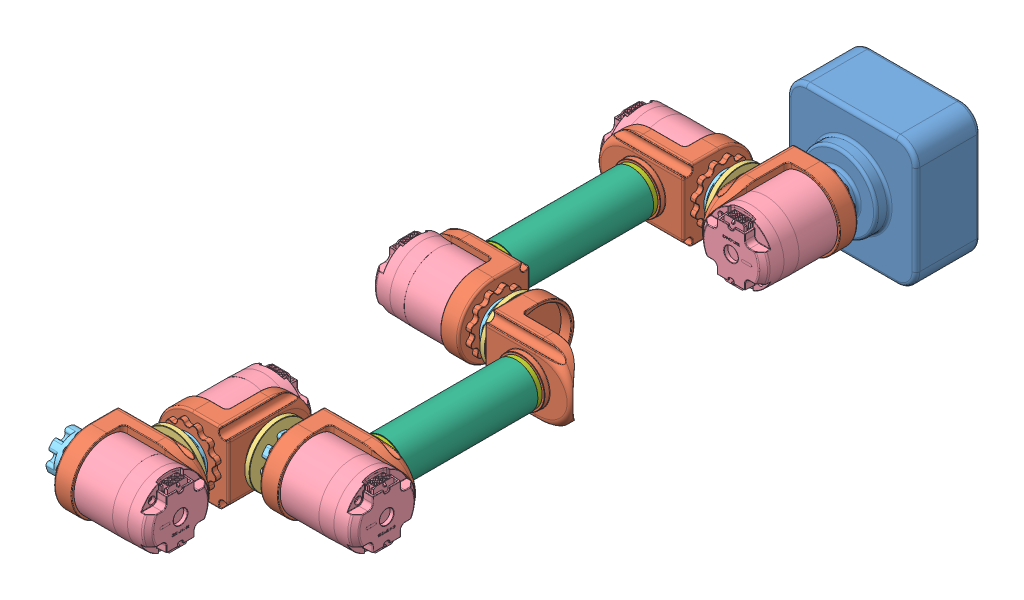
SolidWorks assembly Gluon_6L3_v1_8_1, configuration Default. Lengths in mm.
Overall size (176.02 100 561.85).
34 component instances, 7 part files, 17 mates.
Components (placement in the parent):
- L0-1: L0 [Default] at origin size (100 100 68.87)
- L1^Gluon_6L3_v1_8_1-1: L1^Gluon_6L3_v1_8_1 [Default] at (0.8406 -104.0226 74.9697) size (63.62 67.02 74.77) (virtual)
  - µç»ú¹Ì¶¨¼ÜNE30-1: µç»ú¹Ì¶¨¼ÜNE30 [Default] at (-14.7057 104.0226 11.9) x (0 -1 0) z (0 0 -1) size (55.79 59.62 71.05)
  - Á¬½ÓÅÌNE30-1: Á¬½ÓÅÌNE30 [Default] at (-36.5707 104.0226 30.0576) x (0 0.710457 -0.703741) z (1 0 0) size (47.39 47.39 4)
  - QDD_Lite_NE30-36_v1_8.step-1: QDD_Lite_NE30-36_v1_8.step [Default] at (-0.8163 104.0453 80.659) x (-0.000016 -1 0) z (1 -0.000016 0) size (52.05 68.77 52.02)
- L2^Gluon_6L3_v1_8_1-1: L2^Gluon_6L3_v1_8_1 [Default] at (0.8406 -104.0226 74.9697) size (82.97 55.79 230.2) (virtual)
  - L6-1: L6 [Default] at (-46.7717 104.0226 30.0576) x (0 0.876428 0.481534) z (1 0 0) size (31.45 31.45 14.2)
  - µç»ú¹Ì¶¨¼ÜNE30-1: µç»ú¹Ì¶¨¼ÜNE30 [Default] at (-62.7717 104.0226 43.9226) x (0 1 0) z (1 0 0) size (55.79 59.62 71.05)
  - 30Ì¼¹Ü-1: 30Ì¼¹Ü [Default] at (-80.9293 104.0226 65.7877) x (0.984241 -0.176833 0) z (0 0 1) size (34.33 34.33 102.96)
  - 30Ì¼¹ÜÁ¬½Ó¼þ-1: 30Ì¼¹ÜÁ¬½Ó¼þ [Default] at (-80.9293 104.0226 61.7877) x (0.957931 0.287 0) z (0 0 1) size (33.61 33.61 4)
  - 30Ì¼¹ÜÁ¬½Ó¼þ-2: 30Ì¼¹ÜÁ¬½Ó¼þ [Default] at (-80.9293 104.0226 168.7477) size (33.61 33.61 4)
  - µç»ú¹Ì¶¨¼ÜNE30-2: µç»ú¹Ì¶¨¼ÜNE30 [Default] at (-62.7717 104.0226 190.6128) x (0 -1 0) z (1 0 0) size (55.79 59.62 71.05)
  - L6-2: L6 [Default] at (-46.7717 104.0226 204.4778) x (0 -0.572592 -0.819841) z (1 0 0) size (31.45 31.45 14.2)
  - QDD_Lite_NE30-36_v1_8.step-1: QDD_Lite_NE30-36_v1_8.step [Default] at (-131.5308 104.0453 204.5021) x (0 -1 -0.000016) z (0 -0.000016 1) size (52.05 68.77 52.02)
  - QDD_Lite_NE30-36_v1_8.step-2: QDD_Lite_NE30-36_v1_8.step [Default] at (-131.5308 103.9999 30.0332) x (0 1 0.000016) z (0 0.000016 -1) size (52.05 68.77 52.02)
- L3^Gluon_6L3_v1_8_1-1: L3^Gluon_6L3_v1_8_1 [Default] at (0.8406 -104.0226 74.9697) size (82.97 63.95 234.28) (virtual)
  - L6-1: L6 [Default] at (-30.5707 104.0226 378.8981) x (0 -0.388976 0.921248) z (-1 0 0) size (31.45 31.45 14.2)
  - 30Ì¼¹Ü-1: 30Ì¼¹Ü [Default] at (3.5869 104.0226 240.2079) x (0.999795 0.020268 0) z (0 0 1) size (34.33 34.33 102.96)
  - 30Ì¼¹ÜÁ¬½Ó¼þ-1: 30Ì¼¹ÜÁ¬½Ó¼þ [Default] at (3.5869 104.0226 236.2079) x (0.999973 0.007346 0) z (0 0 1) size (33.61 33.61 4)
  - Á¬½ÓÅÌNE30-1: Á¬½ÓÅÌNE30 [Default] at (-36.5707 104.0226 204.4778) x (0 -0.463223 0.886242) z (1 0 0) size (47.39 47.39 4)
  - µç»ú¹Ì¶¨¼ÜNE30-1: µç»ú¹Ì¶¨¼ÜNE30 [Default] at (-14.5707 104.0226 218.3429) x (0 -1 0) z (-1 0 0) size (55.79 59.62 71.05)
  - µç»ú¹Ì¶¨¼ÜNE30-2: µç»ú¹Ì¶¨¼ÜNE30 [Default] at (-14.5707 104.0226 365.033) x (0 1 0) z (-1 0 0) size (55.79 59.62 71.05)
  - 30Ì¼¹ÜÁ¬½Ó¼þ-2: 30Ì¼¹ÜÁ¬½Ó¼þ [Default] at (3.5869 104.0226 343.1679) size (33.61 33.61 4)
  - QDD_Lite_NE30-36_v1_8.step-1: QDD_Lite_NE30-36_v1_8.step [Default] at (54.1883 103.9999 378.9224) x (0 1 -0.000016) z (0 0.000016 1) size (52.05 68.77 52.02)
- L4^Gluon_6L3_v1_8_1-1: L4^Gluon_6L3_v1_8_1 [Default] at (0.8406 -104.0226 74.9697) size (63.62 55.79 82.97) (virtual)
  - µç»ú¹Ì¶¨¼ÜNE30-1: µç»ú¹Ì¶¨¼ÜNE30 [Default] at (-62.6368 104.0226 397.0557) x (0 -1 0) z (0 0 1) size (55.79 59.62 71.05)
  - L6-1: L6 [Default] at (-76.5019 104.0226 413.0557) x (0.802011 0.597309 0) z (0 0 1) size (31.45 31.45 14.2)
  - Á¬½ÓÅÌNE30-1: Á¬½ÓÅÌNE30 [Default] at (-44.7717 104.0226 378.8981) x (0 0 -1) z (1 0 0) size (47.39 47.39 4)
  - QDD_Lite_NE30-36_v1_8.step-1: QDD_Lite_NE30-36_v1_8.step [Default] at (-76.5262 104.0453 328.2967) x (0.000016 -1 0) z (-1 -0.000016 0) size (52.05 68.77 52.02)
- L5^Gluon_6L3_v1_8_1-1: L5^Gluon_6L3_v1_8_1 [Default] at (0.8406 -104.0226 74.9697) size (88.97 55.79 63.62) (virtual)
  - µç»ú¹Ì¶¨¼ÜNE30-1: µç»ú¹Ì¶¨¼ÜNE30 [Default] at (-94.6595 104.0226 445.1217) x (0 1 0) z (-1 0 0) size (55.79 59.62 71.05)
  - Á¬½ÓÅÌNE30-1: Á¬½ÓÅÌNE30 [Default] at (-76.5019 104.0226 423.2567) x (0.999311 0.037115 0) z (0 0 1) size (47.39 47.39 4)
  - QDD_Lite_NE30-36_v1_8.step-1: QDD_Lite_NE30-36_v1_8.step [Default] at (-25.9005 103.9999 459.0111) x (0 1 -0.000016) z (0 0.000016 1) size (52.05 68.77 52.02)
  - L6-1: L6 [Default] at (-116.6595 104.0226 458.9868) x (0 -0.298091 0.954537) z (-1 0 0) size (31.45 31.45 14.2)
Mates (geometry in assembly coordinates):
- Coincident1: coincident anti-aligned: plane of L0-1 through (0 0 68.8696) normal (0 0 1); plane of L1^Gluon_6L3_v1_8_1-1/µç»ú¹Ì¶¨¼ÜNE30-1 through (0 0 68.8696) normal (0 0 -1)
- Concentric1: concentric anti-aligned: cylinder of L0-1 through (0 0 68.8696) axis (0 0 -1) radius 15.8945; cylinder of L1^Gluon_6L3_v1_8_1-1/µç»ú¹Ì¶¨¼ÜNE30-1 through (0 0 72.8696) axis (0 0 1) radius 27.8875
- Coincident2: coordinate: unknown of L0-1
- Coincident3: coincident anti-aligned: plane of L1^Gluon_6L3_v1_8_1-1/Á¬½ÓÅÌNE30-1 through (-35.7301 0 105.0272) normal (-1 0 0); plane of L2^Gluon_6L3_v1_8_1-1/L6-1 through (-35.7301 0 105.0272) normal (1 0 0)
- Concentric2: concentric aligned: cylinder of L1^Gluon_6L3_v1_8_1-1/Á¬½ÓÅÌNE30-1 through (-31.7301 0 105.0272) axis (-1 0 0) radius 23.6944; cylinder of L2^Gluon_6L3_v1_8_1-1/L6-1 through (-35.7301 0 105.0272) axis (-1 0 0) radius 15.7247
- Coincident4: coincident anti-aligned: plane of L2^Gluon_6L3_v1_8_1-1/L6-2 through (-35.7301 0 279.4475) normal (1 0 0); plane of L3^Gluon_6L3_v1_8_1-1/Á¬½ÓÅÌNE30-1 through (-35.7301 0 279.4475) normal (-1 0 0)
- Concentric3: concentric aligned: cylinder of L2^Gluon_6L3_v1_8_1-1/L6-2 through (-35.7301 0 279.4475) axis (-1 0 0) radius 15.7247; cylinder of L3^Gluon_6L3_v1_8_1-1/Á¬½ÓÅÌNE30-1 through (-31.7301 0 279.4475) axis (-1 0 0) radius 23.6944
- Coincident5: coincident anti-aligned: plane of L3^Gluon_6L3_v1_8_1-1/L6-1 through (-39.9311 0 453.8678) normal (-1 0 0); plane of L4^Gluon_6L3_v1_8_1-1/Á¬½ÓÅÌNE30-1 through (-39.9311 0 453.8678) normal (1 0 0)
- Concentric4: concentric anti-aligned: cylinder of L3^Gluon_6L3_v1_8_1-1/L6-1 through (-39.9311 0 453.8678) axis (1 0 0) radius 15.7247; cylinder of L4^Gluon_6L3_v1_8_1-1/Á¬½ÓÅÌNE30-1 through (-39.9311 0 453.8678) axis (-1 0 0) radius 23.6944
- Coincident6: coincident anti-aligned: plane of L4^Gluon_6L3_v1_8_1-1/L6-1 through (-75.6613 0 498.2264) normal (0 0 1); plane of L5^Gluon_6L3_v1_8_1-1/Á¬½ÓÅÌNE30-1 through (-75.6613 0 498.2264) normal (0 0 -1)
- Concentric5: concentric aligned: cylinder of L4^Gluon_6L3_v1_8_1-1/L6-1 through (-75.6613 0 498.2264) axis (0 0 -1) radius 15.7247; cylinder of L5^Gluon_6L3_v1_8_1-1/Á¬½ÓÅÌNE30-1 through (-75.6613 0 502.2264) axis (0 0 -1) radius 23.6944
- Parallel1: parallel aligned: plane of L2^Gluon_6L3_v1_8_1-1 through (0.8406 -104.0226 74.9697) normal (0 0 1)
- Parallel2: parallel aligned: plane of L3^Gluon_6L3_v1_8_1-1 through (0.8406 -104.0226 74.9697) normal (0 0 1)
- Parallel3: parallel aligned: plane of L4^Gluon_6L3_v1_8_1-1 through (0.8406 -104.0226 74.9697) normal (0 0 1)
- Parallel5: parallel aligned: plane of L1^Gluon_6L3_v1_8_1-1 through (0.8406 -104.0226 74.9697) normal (0 1 0)
- Parallel6: parallel aligned: plane of L2^Gluon_6L3_v1_8_1-1 through (0.8406 -104.0226 74.9697) normal (0 1 0)
- Parallel7: parallel aligned: plane of L5^Gluon_6L3_v1_8_1-1 through (0.8406 -104.0226 74.9697) normal (0 1 0)
